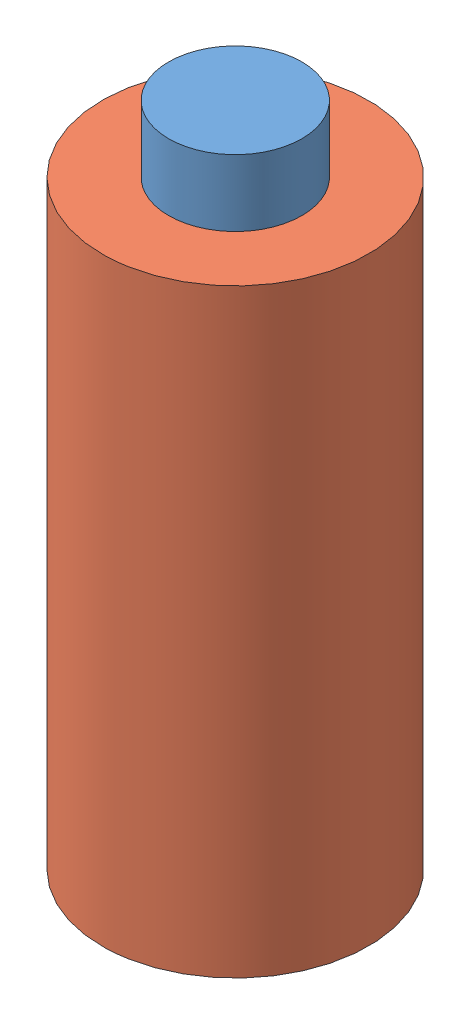
SolidWorks assembly Assem2, configuration Default. Lengths in mm.
Overall size (21.97 50 21.97).
2 component instances, 2 part files, 2 mates.
Components (placement in the parent):
- Magnet 1-1: Magnet 1 [Default] at (3.8689 4.7653 6.2135) size (10 5 10)
- Dowel 1-1: Dowel 1 [Default] at (3.8689 -40.2347 6.2135) x (0.994608 0 -0.103709) z (0.103709 0 0.994608) size (20 45 20)
Mates (geometry in assembly coordinates):
- Concentric1: concentric: cylinder of Magnet 1-1 through (3.8689 9.7653 6.2135) axis (0 -1 0) radius 5; cylinder of Dowel 1-1 through (3.8689 4.7653 6.2135) axis (0 -1 0) radius 10
- Coincident1: coincident anti-aligned: plane of Magnet 1-1 through (3.8689 4.7653 6.2135) normal (0 -1 0); plane of Dowel 1-1 through (3.8689 4.7653 6.2135) normal (0 1 0)
